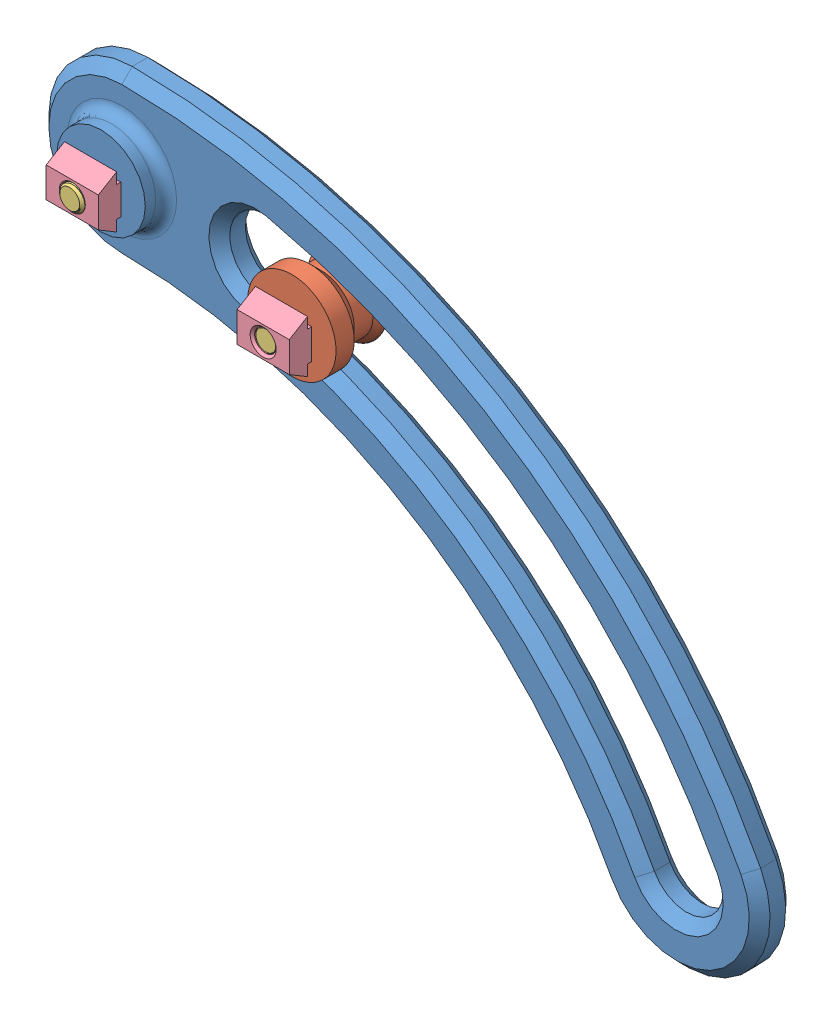
SolidWorks assembly Lid_Stop, configuration Default. Lengths in mm.
Overall size (138.3 96.32 20.24).
6 component instances, 4 part files, 10 mates.
Components (placement in the parent):
- Lid_Stop-1: Lid_Stop [Default] at origin size (138.3 96.32 11)
- Lid_Stop_Peg-1: Lid_Stop_Peg [Default] at (117.7216 -99.8249 0) x (-0.950729 0.310024 0) z (0 0 1) size (16.94 16.94 11)
- 5mmX16mm_Buttonhead(McMaster_91239A232)-1: 5mmX16mm_Buttonhead(McMaster_91239A232) [91239A232] at (0 0 -1.75) x (-0.414442 -0.910076 0) z (0 0 -1) size (9.5 9.5 19.24)
- 5mmX16mm_Buttonhead(McMaster_91239A232)-2: 5mmX16mm_Buttonhead(McMaster_91239A232) [91239A232] at (36.5995 -5.7176 -2.75) x (0.299081 -0.954228 0) z (0 0 -1) size (9.5 9.5 19.24)
- HNTTSN5-5-2: HNTTSN5-5 [Default] at (36.5995 -5.7176 12.2) x (0 0 -1) z (1 0 0) size (4.3 10 10)
- HNTTSN5-5-3: HNTTSN5-5 [Default] at (0 0 12.2) x (0 0 -1) z (1 0 0) size (4.3 10 10)
Mates (geometry in assembly coordinates):
- Coincident1: coincident aligned: plane of Lid_Stop-1 through (0 0 11) normal (0 0 1); plane of Lid_Stop_Peg-1 through (28.5472 -3.0918 11) normal (0 0 1)
- Slot1: slot aligned: cylinder of Lid_Stop_Peg-1 through (36.5995 -5.7176 11) axis (0 0 -1) radius 6.25; cylinder of Lid_Stop-1 through (0 -120 7) axis (0 0 -1) radius 127; cylinder of Lid_Stop-1 through (106.3006 -64.3208 7) axis (0 0 -1) radius 7
- Concentric2: concentric aligned: cylinder of Lid_Stop-1 through (0 0 7) axis (0 0 -1) radius 2.55; cylinder of 5mmX16mm_Buttonhead(McMaster_91239A232)-1 through (0 0 -1.75) axis (0 0 -1) radius 4.75
- Distance1: distance = 6 mm aligned: plane of Lid_Stop-1 through (0 0 11) normal (0 0 1); plane of 5mmX16mm_Buttonhead(McMaster_91239A232)-1 through (2.2752 -1.0361 17) normal (0 0 1)
- Concentric3: concentric aligned: cylinder of Lid_Stop_Peg-1 through (36.5995 -5.7176 0) axis (0 0 -1) radius 2.55; cylinder of 5mmX16mm_Buttonhead(McMaster_91239A232)-2 through (36.5995 -5.7176 -2.75) axis (0 0 -1) radius 4.75
- Coincident3: coincident anti-aligned: plane of Lid_Stop_Peg-1 through (36.5995 -5.7176 0) normal (0 0 -1); plane of 5mmX16mm_Buttonhead(McMaster_91239A232)-2 through (41.1321 -4.2969 0) normal (0 0 1)
- Concentric5: concentric anti-aligned: cylinder of Lid_Stop-1 through (0 0 7) axis (0 0 -1) radius 2.55; cylinder of HNTTSN5-5-3 through (0 0 12.2) axis (0 0 1) radius 2.067
- Concentric6: concentric anti-aligned: cylinder of Lid_Stop_Peg-1 through (36.5995 -5.7176 0) axis (0 0 -1) radius 2.55; cylinder of HNTTSN5-5-2 through (36.5995 -5.7176 12.2) axis (0 0 1) radius 2.067
- Distance2: distance = 2 mm anti-aligned: plane of HNTTSN5-5-2 through (41.5995 -10.7176 13) normal (0 0 -1); plane of Lid_Stop_Peg-1 through (28.5472 -3.0918 11) normal (0 0 1)
- Distance3: distance = 2 mm anti-aligned: plane of Lid_Stop-1 through (0 0 11) normal (0 0 1); plane of HNTTSN5-5-3 through (5 -5 13) normal (0 0 -1)
